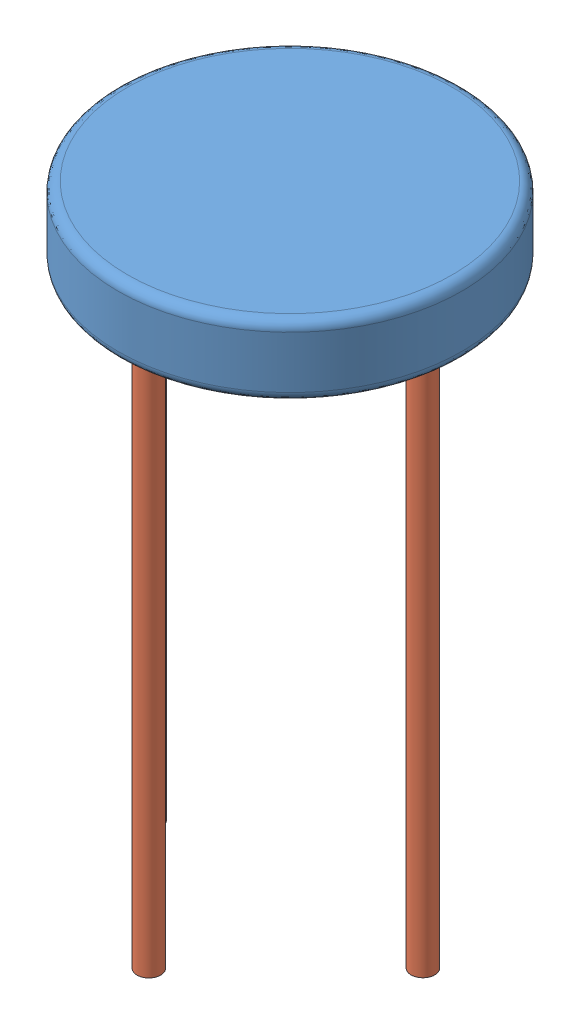
SolidWorks assembly Stool Assembly, configuration Default. Lengths in mm.
Overall size (368.3 660.4 368.3).
5 component instances, 2 part files, 3 mates.
Components (placement in the parent):
- Stool-1: Stool [Default] at (128.1086 151.1067 315.5626) size (368.3 76.2 368.3)
- Stool Leg-1: Stool Leg [Default] at (122.4932 -433.0933 461.0857) size (25.4 584.2 25.4)
- Stool Leg-2: Stool Leg [Default] at (124.8567 -433.0933 170.0812) size (25.4 584.2 25.4)
- Stool Leg-3: Stool Leg [Default] at (269.1281 151.1067 314.1487) x (-0.837169 0 -0.546944) z (-0.546944 0 0.837169) size (25.4 584.2 25.4)
- Stool Leg-4: Stool Leg [Default] at (-14.4052 -433.0933 323.2334) size (25.4 584.2 25.4)
Mates (geometry in assembly coordinates):
- Coincident1: coincident anti-aligned: plane of Stool-1 through (128.1086 151.1067 315.5626) normal (0 -1 0); plane of Stool Leg-1 through (122.4932 151.1067 461.0857) normal (0 1 0)
- Coincident21: coincident anti-aligned: plane of Stool-1 through (128.1086 151.1067 315.5626) normal (0 -1 0); plane of Stool Leg-3 through (269.1281 151.1067 314.1487) normal (0 1 0)
- Coincident3: coincident anti-aligned: plane of Stool-1 through (128.1086 151.1067 315.5626) normal (0 -1 0); plane of Stool Leg-2 through (124.8567 151.1067 170.0812) normal (0 1 0)
